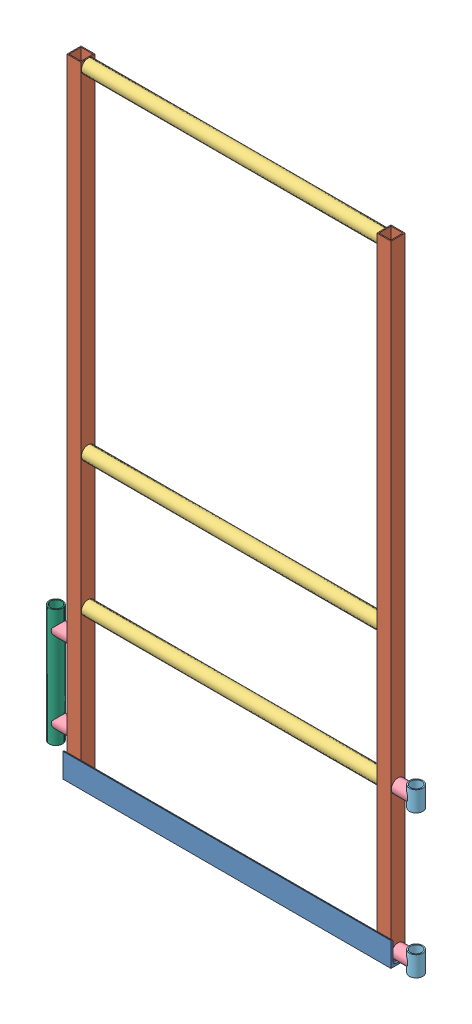
SolidWorks assembly GE-18012, configuration Default. Lengths in mm.
Overall size (1178.81 1981.2 76.2).
13 component instances, 6 part files, 42 mates.
Components (placement in the parent):
- GE-18012-01-1: GE-18012-01 [Default] at (-517.525 0 0) x (1 0 0) z (0 1 0) size (1035.05 76.2 76.2)
- GE-18012-02-1: GE-18012-02 [Default] at (-1501.775 0 0) x (1 0 0) z (0 1 0) size (44.45 44.45 1974.85)
- GE-18012-02-2: GE-18012-02 [Default] at (-523.875 0 0) x (1 0 0) z (0 1 0) size (44.45 44.45 1974.85)
- GE-18012-03-1: GE-18012-03 [Default] at (-523.875 1931.543 -1987.55) size (933.45 42.16 42.16)
- GE-18012-03-2: GE-18012-03 [Default] at (-523.875 875.157 -1987.55) size (933.45 42.16 42.16)
- GE-18012-03-3: GE-18012-03 [Default] at (-523.875 451.993 -1987.55) size (933.45 42.16 42.16)
- GE-18012-04-1: GE-18012-04 [Default] at (-523.875 0 0) x (1 0 0) z (0 1 0) size (50.8 42.16 42.16)
- GE-18012-04-2: GE-18012-04 [Default] at (-523.875 514.35 -57.15) x (1 0 0) z (0 -1 0) size (50.8 42.16 42.16)
- GE-18012-04-3: GE-18012-04 [Default] at (-511.175 347.218 -57.15) x (-1 0 0) z (0 1 0) size (50.8 42.16 42.16)
- GE-18012-04-4: GE-18012-04 [Default] at (-511.175 94.107 -57.15) x (-1 0 0) z (0 1 0) size (50.8 42.16 42.16)
- GE-18012-05-1: GE-18012-05 [Default] at (-523.875 450.85 0) x (1 0 0) z (0 1 0) size (42.16 42.16 63.5)
- GE-18012-05-2: GE-18012-05 [Default] at (-523.875 63.5 -57.15) x (1 0 0) z (0 -1 0) size (42.16 42.16 63.5)
- GE-18012-06-1: GE-18012-06 [Default] at (-517.525 438.15 -50.8) x (1 0 0) z (0 -1 0) size (42.16 42.16 371.48)
Mates (geometry in assembly coordinates):
- Coincident1: coincident anti-aligned: plane of GE-18012-01-1 through (0 0 -38.1) normal (0 -1 0); plane of assembly through (0 0 0) normal (0 1 0)
- Coincident2: coincident aligned: plane of GE-18012-01-1 through (0 38.1 0) normal (0 0 1); plane of assembly through (0 0 0) normal (0 0 1)
- Coincident3: coincident aligned: plane of GE-18012-01-1 through (0 38.1 -38.1) normal (1 0 0); plane of assembly through (0 0 0) normal (1 0 0)
- Coincident4: coincident anti-aligned: plane of GE-18012-01-1 through (0 6.35 -41.275) normal (0 1 0); plane of GE-18012-02-2 through (-50.8 6.35 -41.275) normal (0 -1 0)
- Distance1: distance = 6.35 mm aligned: plane of GE-18012-02-2 through (-6.35 990.6 -38.1) normal (1 0 0); plane of GE-18012-01-1 through (0 38.1 -38.1) normal (1 0 0)
- Coincident6: coincident anti-aligned: plane of GE-18012-01-1 through (0 41.275 -6.35) normal (0 0 -1); plane of GE-18012-02-2 through (-50.8 87.0439 -6.35) normal (0 0 1)
- Coincident7: coincident anti-aligned: plane of GE-18012-01-1 through (0 6.35 -41.275) normal (0 1 0); plane of GE-18012-02-1 through (-1028.7 6.35 -41.275) normal (0 -1 0)
- Distance2: distance = 6.35 mm aligned: plane of GE-18012-02-1 through (-1028.7 990.6 -38.1) normal (-1 0 0); plane of GE-18012-01-1 through (-1035.05 38.1 -38.1) normal (-1 0 0)
- Coincident9: coincident anti-aligned: plane of GE-18012-01-1 through (0 41.275 -6.35) normal (0 0 -1); plane of GE-18012-02-1 through (-1028.7 87.0439 -6.35) normal (0 0 1)
- Coincident10: coincident anti-aligned: plane of GE-18012-02-2 through (-50.8 990.6 -38.1) normal (-1 0 0); plane of GE-18012-03-3 through (-50.8 490.093 -996.95) normal (1 0 0)
- Distance3: distance = 480.568 mm: cylinder of GE-18012-03-3 through (-50.798 480.568 -28.575) axis (1 0 0) radius 21.082; plane of GE-18012-01-1 through (0 0 -38.1) normal (0 -1 0)
- Distance4: distance = 22.225 mm: plane of GE-18012-02-2 through (-50.8 87.0439 -6.35) normal (0 0 1); cylinder of GE-18012-03-3 through (-50.798 480.568 -28.575) axis (1 0 0) radius 21.082
- Coincident11: coincident anti-aligned: plane of GE-18012-02-2 through (-50.8 990.6 -38.1) normal (-1 0 0); plane of GE-18012-03-2 through (-50.8 913.257 -996.95) normal (1 0 0)
- Distance5: distance = 22.225 mm: cylinder of GE-18012-03-2 through (-50.798 903.732 -28.575) axis (1 0 0) radius 21.082; plane of GE-18012-02-2 through (-50.8 87.0439 -6.35) normal (0 0 1)
- Distance6: distance = 903.732 mm: cylinder of GE-18012-03-2 through (-50.798 903.732 -28.575) axis (1 0 0) radius 21.082; plane of GE-18012-01-1 through (0 0 -38.1) normal (0 -1 0)
- Coincident12: coincident anti-aligned: plane of GE-18012-02-2 through (-50.8 990.6 -38.1) normal (-1 0 0); plane of GE-18012-03-1 through (-50.8 1969.643 -996.95) normal (1 0 0)
- Distance7: distance = 22.225 mm: cylinder of GE-18012-03-1 through (-50.798 1960.118 -28.575) axis (1 0 0) radius 21.082; plane of GE-18012-02-2 through (-50.8 87.0439 -6.35) normal (0 0 1)
- Tangent6: tangent aligned: plane of GE-18012-02-2 through (-50.8 1981.2 -28.8192) normal (0 1 0); cylinder of GE-18012-03-1 through (-50.798 1960.118 -28.575) axis (1 0 0) radius 21.082
- Parallel1: parallel aligned: plane of GE-18012-03-1 through (-523.875 1931.543 -1987.55) normal (0 1 0); plane of assembly through (0 0 0) normal (0 1 0)
- Parallel2: parallel aligned: plane of GE-18012-03-2 through (-523.875 875.157 -1987.55) normal (0 1 0); plane of assembly through (0 0 0) normal (0 1 0)
- Parallel3: parallel aligned: plane of GE-18012-03-3 through (-523.875 451.993 -1987.55) normal (0 1 0); plane of assembly through (0 0 0) normal (0 1 0)
- Coincident16: coincident anti-aligned: plane of GE-18012-02-2 through (-6.35 990.6 -38.1) normal (1 0 0); plane of GE-18012-04-2 through (-6.35 -479.425 -28.575) normal (-1 0 0)
- Distance8: distance = 22.225 mm: cylinder of GE-18012-04-2 through (44.45 482.6 -28.575) axis (1 0 0) radius 21.082; plane of GE-18012-02-2 through (-50.8 87.0439 -6.35) normal (0 0 1)
- Coincident17: coincident anti-aligned: plane of GE-18012-02-2 through (-6.35 990.6 -38.1) normal (1 0 0); plane of GE-18012-04-1 through (-6.35 993.775 -28.575) normal (-1 0 0)
- Distance9: distance = 22.225 mm: cylinder of GE-18012-04-1 through (44.45 31.75 -28.575) axis (1 0 0) radius 21.082; plane of GE-18012-02-2 through (-50.8 87.0439 -6.35) normal (0 0 1)
- Parallel4: parallel anti-aligned: plane of GE-18012-01-1 through (0 0 -38.1) normal (0 -1 0); plane of GE-18012-04-1 through (-523.875 0 0) normal (0 1 0)
- Concentric1: concentric anti-aligned: cylinder of GE-18012-04-1 through (50.8 76.2 -28.575) axis (0 1 0) radius 21.082; cylinder of GE-18012-05-2 through (50.8 0 -28.575) axis (0 -1 0) radius 21.082
- Coincident19: coincident aligned: plane of GE-18012-01-1 through (0 0 -38.1) normal (0 -1 0); plane of GE-18012-05-2 through (-484.759 0 -19.05) normal (0 -1 0)
- Concentric2: concentric anti-aligned: cylinder of GE-18012-05-1 through (50.8 514.35 -28.575) axis (0 1 0) radius 21.082; cylinder of GE-18012-05-2 through (50.8 0 -28.575) axis (0 -1 0) radius 21.082
- Distance11: distance = 450.85 mm aligned: plane of GE-18012-05-1 through (-484.759 450.85 -38.1) normal (0 -1 0); plane of GE-18012-01-1 through (0 0 -38.1) normal (0 -1 0)
- Distance13: distance = 31.75 mm: plane of GE-18012-05-2 through (-484.759 63.5 -19.05) normal (0 1 0); cylinder of GE-18012-04-1 through (44.45 31.75 -28.575) axis (1 0 0) radius 17.526
- Parallel5: parallel anti-aligned: cylinder of GE-18012-04-2 through (50.8 438.15 -28.575) axis (0 -1 0) radius 21.082; cylinder of GE-18012-05-1 through (50.8 514.35 -28.575) axis (0 1 0) radius 21.082
- Distance14: distance = 31.75 mm: cylinder of GE-18012-04-2 through (44.45 482.6 -28.575) axis (1 0 0) radius 17.526; plane of GE-18012-05-1 through (-484.759 514.35 -38.1) normal (0 1 0)
- Coincident21: coincident anti-aligned: plane of GE-18012-02-1 through (-1028.7 990.6 -38.1) normal (-1 0 0); plane of GE-18012-04-4 through (-1028.7 1087.882 -28.575) normal (1 0 0)
- Distance15: distance = 22.225 mm: cylinder of GE-18012-04-4 through (-1079.5 125.857 -28.575) axis (-1 0 0) radius 21.082; plane of GE-18012-02-1 through (-1028.7 87.0439 -6.35) normal (0 0 1)
- Coincident22: coincident anti-aligned: plane of GE-18012-02-1 through (-1028.7 990.6 -38.1) normal (-1 0 0); plane of GE-18012-04-3 through (-1028.7 1340.993 -28.575) normal (1 0 0)
- Distance16: distance = 22.225 mm: plane of GE-18012-02-1 through (-1028.7 87.0439 -6.35) normal (0 0 1); cylinder of GE-18012-04-3 through (-1079.5 378.968 -28.575) axis (-1 0 0) radius 21.082
- Distance17: distance = 66.675 mm aligned: plane of GE-18012-06-1 through (-553.466 66.675 -12.7) normal (0 -1 0); plane of GE-18012-01-1 through (0 0 -38.1) normal (0 -1 0)
- Concentric4: concentric anti-aligned: cylinder of GE-18012-04-4 through (-1085.85 170.307 -28.575) axis (0 1 0) radius 21.082; cylinder of GE-18012-06-1 through (-1085.85 66.675 -28.575) axis (0 -1 0) radius 21.082
- Parallel6: parallel anti-aligned: cylinder of GE-18012-04-3 through (-1085.85 423.418 -28.575) axis (0 1 0) radius 21.082; cylinder of GE-18012-06-1 through (-1085.85 66.675 -28.575) axis (0 -1 0) radius 21.082
- Distance18: distance = 38.1 mm: cylinder of GE-18012-04-4 through (-1079.5 125.857 -28.575) axis (-1 0 0) radius 21.082; plane of GE-18012-06-1 through (-553.466 66.675 -12.7) normal (0 -1 0)
- Distance19: distance = 38.1 mm: cylinder of GE-18012-04-3 through (-1079.5 378.968 -28.575) axis (-1 0 0) radius 21.082; plane of GE-18012-06-1 through (-553.466 438.15 -12.7) normal (0 1 0)
